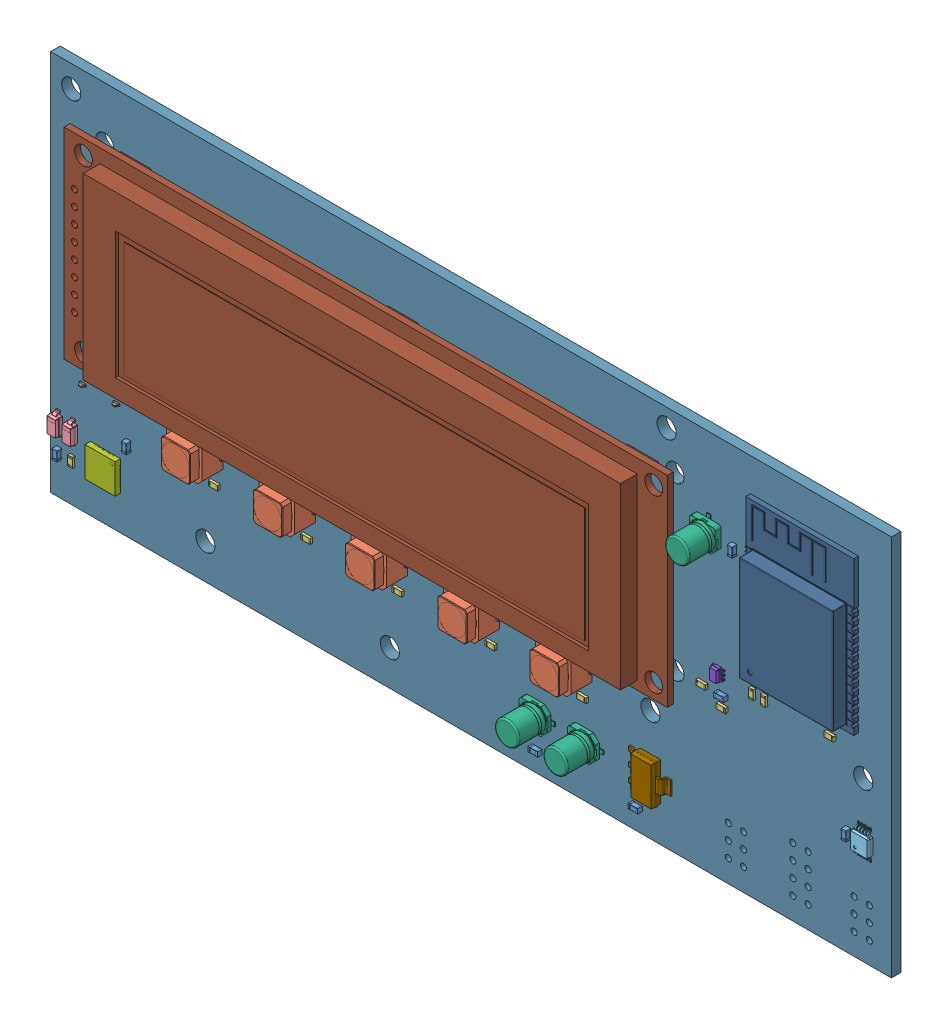
SolidWorks assembly MiliOhmMeter, configuration Default. Lengths in mm.
Overall size (140.08 63.63 18.73).
86 component instances, 14 part files, 0 mates.
Components (placement in the parent):
- MiliOhmMeter.step-1: MiliOhmMeter.step [Default] at origin size (140.08 63.63 18.73)
  - C_0603_1608Metric.step-1: C_0603_1608Metric.step [Default] at (62.9031 -14.3637 1.65) x (0 -1 0) z (0 0 1) size (1.6 0.8 0.8)
    - SOLID.step-1: SOLID.step [Default] at origin size (1.6 0.8 0.8)
  - C_0603_1608Metric.step-2: C_0603_1608Metric.step [Default] at (-15.1635 -16.8021 1.65) size (1.6 0.8 0.8)
    - SOLID.step-1: SOLID.step [Default] at origin size (1.6 0.8 0.8)
  - C_0603_1608Metric.step-3: C_0603_1608Metric.step [Default] at (-68.5419 -25.2603 1.65) x (0 -1 0) z (0 0 1) size (1.6 0.8 0.8)
    - SOLID.step-1: SOLID.step [Default] at origin size (1.6 0.8 0.8)
  - SW_SPST_Alps_SKPMAME010.step-1: SW_SPST_Alps_SKPMAME010.step [Default] at (-28.2355 -11.4021 1.65) x (1 0 0) z (0 -1 0) size (6.7 5 6)
    - COMPOUND.step-1: COMPOUND.step [Default] at origin size (6.7 5 6)
  - R_0603_1608Metric.step-1: R_0603_1608Metric.step [Default] at (47.1043 -2.0701 1.65) x (0 -1 0) z (0 0 1) size (1.6 0.8 0.45)
    - SOLID-0.step-1: SOLID-0.step [Default] at origin size (1.6 0.8 0.45)
  - D_SOD-123.step-1: D_SOD-123.step [Default] at (-68.6435 -20.9931 1.65) x (0 -1 0) z (0 0 1) size (3.8 1.6 1.25)
    - SOLID-1.step-1: SOLID-1.step [Default] at origin size (3.8 1.6 1.25)
  - C_0603_1608Metric.step-4: C_0603_1608Metric.step [Default] at (15.5575 -16.8021 1.65) size (1.6 0.8 0.8)
    - SOLID.step-1: SOLID.step [Default] at origin size (1.6 0.8 0.8)
  - SW_SPST_Alps_SKPMAME010.step-2: SW_SPST_Alps_SKPMAME010.step [Default] at (-12.8755 -11.4021 1.65) x (1 0 0) z (0 -1 0) size (6.7 5 6)
    - COMPOUND.step-1: COMPOUND.step [Default] at origin size (6.7 5 6)
  - R_0603_1608Metric.step-2: R_0603_1608Metric.step [Default] at (-27.1145 -16.8021 1.65) x (-1 0 0) z (0 0 1) size (1.6 0.8 0.45)
    - SOLID-0.step-1: SOLID-0.step [Default] at origin size (1.6 0.8 0.45)
  - C_0603_1608Metric.step-5: C_0603_1608Metric.step [Default] at (0.3175 -16.8021 1.65) size (1.6 0.8 0.8)
    - SOLID.step-1: SOLID.step [Default] at origin size (1.6 0.8 0.8)
  - SW_SPST_Alps_SKPMAME010.step-3: SW_SPST_Alps_SKPMAME010.step [Default] at (17.8445 -11.4021 1.65) x (1 0 0) z (0 -1 0) size (6.7 5 6)
    - COMPOUND.step-1: COMPOUND.step [Default] at origin size (6.7 5 6)
  - TSSOP-10_3x3mm_P0.5mm.step-1: TSSOP-10_3x3mm_P0.5mm.step [Default] at (65.659 -14.2621 1.65) x (0 1 0) z (0 0 1) size (4.9 3 1)
    - SOLID-2.step-1: SOLID-2.step [Default] at origin size (4.9 3 1)
  - C_Elec_4x5.4.step-1: C_Elec_4x5.4.step [Default] at (11.3665 -23.1521 1.65) x (-1 0 0) z (0 0 1) size (5.74 5.46 5.4)
    - COMPOUND-3.step-1: COMPOUND-3.step [Default] at origin size (5.74 5.46 5.4)
  - D_SOD-123.step-2: D_SOD-123.step [Default] at (-66.1289 -20.9931 1.65) x (0 -1 0) z (0 0 1) size (3.8 1.6 1.25)
    - SOLID-1.step-1: SOLID-1.step [Default] at origin size (3.8 1.6 1.25)
  - R_0603_1608Metric.step-3: R_0603_1608Metric.step [Default] at (-11.8745 -16.8021 1.65) x (-1 0 0) z (0 0 1) size (1.6 0.8 0.45)
    - SOLID-0.step-1: SOLID-0.step [Default] at origin size (1.6 0.8 0.45)
  - SW_SPST_Alps_SKPMAME010.step-4: SW_SPST_Alps_SKPMAME010.step [Default] at (2.4845 -11.4021 1.65) x (1 0 0) z (0 -1 0) size (6.7 5 6)
    - COMPOUND.step-1: COMPOUND.step [Default] at origin size (6.7 5 6)
  - R_0603_1608Metric.step-4: R_0603_1608Metric.step [Default] at (42.1005 -6.6421 1.65) x (-1 0 0) z (0 0 1) size (1.6 0.8 0.45)
    - SOLID-0.step-1: SOLID-0.step [Default] at origin size (1.6 0.8 0.45)
  - C_0603_1608Metric.step-6: C_0603_1608Metric.step [Default] at (42.0497 -4.9149 1.65) x (-1 0 0) z (0 0 1) size (1.6 0.8 0.8)
    - SOLID.step-1: SOLID.step [Default] at origin size (1.6 0.8 0.8)
  - C_0603_1608Metric.step-7: C_0603_1608Metric.step [Default] at (-30.4165 -16.8021 1.65) size (1.6 0.8 0.8)
    - SOLID.step-1: SOLID.step [Default] at origin size (1.6 0.8 0.8)
  - R_0603_1608Metric.step-5: R_0603_1608Metric.step [Default] at (49.0855 -2.0701 1.65) x (0 1 0) z (0 0 1) size (1.6 0.8 0.45)
    - SOLID-0.step-1: SOLID-0.step [Default] at origin size (1.6 0.8 0.45)
  - C_Elec_4x5.4.step-2: C_Elec_4x5.4.step [Default] at (39.7129 17.3355 1.65) x (0 1 0) z (0 0 1) size (5.74 5.46 5.4)
    - COMPOUND-3.step-1: COMPOUND-3.step [Default] at origin size (5.74 5.46 5.4)
  - R_0603_1608Metric.step-6: R_0603_1608Metric.step [Default] at (-66.3321 -25.2603 1.65) x (0 -1 0) z (0 0 1) size (1.6 0.8 0.45)
    - SOLID-0.step-1: SOLID-0.step [Default] at origin size (1.6 0.8 0.45)
  - R_0603_1608Metric.step-7: R_0603_1608Metric.step [Default] at (18.8595 -16.8021 1.65) x (-1 0 0) z (0 0 1) size (1.6 0.8 0.45)
    - SOLID-0.step-1: SOLID-0.step [Default] at origin size (1.6 0.8 0.45)
  - QFN-28-1EP_5x5mm_P0.5mm_EP3.35x3.35mm.step-1: QFN-28-1EP_5x5mm_P0.5mm_EP3.35x3.35mm.step [Default] at (-60.833 -23.5331 1.65) x (0 -1 0) z (0 0 1) size (5 5 0.92)
    - SOLID-4.step-1: SOLID-4.step [Default] at origin size (5 5 0.92)
  - R_0603_1608Metric.step-8: R_0603_1608Metric.step [Default] at (-42.5069 -16.8021 1.65) x (-1 0 0) z (0 0 1) size (1.6 0.8 0.45)
    - SOLID-0.step-1: SOLID-0.step [Default] at origin size (1.6 0.8 0.45)
  - C_0603_1608Metric.step-8: C_0603_1608Metric.step [Default] at (-57.0103 -18.4531 1.65) x (0 1 0) z (0 0 1) size (1.6 0.8 0.8)
    - SOLID.step-1: SOLID.step [Default] at origin size (1.6 0.8 0.8)
  - C_0603_1608Metric.step-9: C_0603_1608Metric.step [Default] at (27.7749 -28.1051 1.65) x (-1 0 0) z (0 0 1) size (1.6 0.8 0.8)
    - SOLID.step-1: SOLID.step [Default] at origin size (1.6 0.8 0.8)
  - SW_SPST_Alps_SKPMAME010.step-5: SW_SPST_Alps_SKPMAME010.step [Default] at (-43.5955 -11.4021 1.65) x (1 0 0) z (0 -1 0) size (6.7 5 6)
    - COMPOUND.step-1: COMPOUND.step [Default] at origin size (6.7 5 6)
  - R_0603_1608Metric.step-9: R_0603_1608Metric.step [Default] at (3.6195 -16.8021 1.65) x (-1 0 0) z (0 0 1) size (1.6 0.8 0.45)
    - SOLID-0.step-1: SOLID-0.step [Default] at origin size (1.6 0.8 0.45)
  - SOT-363_SC-70-6.step-1: SOT-363_SC-70-6.step [Default] at (41.402 -1.9431 1.65) size (2 2 1.05)
    - SOLID-5.step-1: SOLID-5.step [Default] at origin size (2 2 1.05)
  - C_0603_1608Metric.step-10: C_0603_1608Metric.step [Default] at (43.9547 17.1069 1.65) x (0 1 0) z (0 0 1) size (1.6 0.8 0.8)
    - SOLID.step-1: SOLID.step [Default] at origin size (1.6 0.8 0.8)
  - R_0603_1608Metric.step-10: R_0603_1608Metric.step [Default] at (60.0837 -1.7399 1.65) x (-1 0 0) z (0 0 1) size (1.6 0.8 0.45)
    - SOLID-0.step-1: SOLID-0.step [Default] at origin size (1.6 0.8 0.45)
  - SOT-223.step-1: SOT-223.step [Default] at (30.0605 -22.5679 1.65) size (7 6.5 1.7)
    - SOLID-6.step-1: SOLID-6.step [Default] at origin size (7 6.5 1.7)
  - R_0603_1608Metric.step-11: R_0603_1608Metric.step [Default] at (38.7223 -4.9403 1.65) size (1.6 0.8 0.45)
    - SOLID-0.step-1: SOLID-0.step [Default] at origin size (1.6 0.8 0.45)
  - ESP32-WROOM-32.step-1: ESP32-WROOM-32.step [Default] at (55.626 10.6299 1.65) size (18 25.5 3.1)
    - SOLID-7.step-1: SOLID-7.step [Default] at origin size (18 25.5 3.1)
  - C_0603_1608Metric.step-11: C_0603_1608Metric.step [Default] at (11.1125 -28.2321 1.65) x (-1 0 0) z (0 0 1) size (1.6 0.8 0.8)
    - SOLID.step-1: SOLID.step [Default] at origin size (1.6 0.8 0.8)
  - OLED_SSD1322_NHD_256X64.step-1: OLED_SSD1322_NHD_256X64.step [Default] at (-104.132 5.9279 4.15) x (-1 0 0) z (0 1 0) size (100.5 6.3 33.5)
    - COMPOUND-8.step-1: COMPOUND-8.step [Default] at origin size (100.5 6.3 33.5)
  - C_0603_1608Metric.step-12: C_0603_1608Metric.step [Default] at (-45.9105 -16.8021 1.65) size (1.6 0.8 0.8)
    - SOLID.step-1: SOLID.step [Default] at origin size (1.6 0.8 0.8)
  - C_Elec_4x5.4.step-3: C_Elec_4x5.4.step [Default] at (19.4433 -23.1775 1.65) x (-1 0 0) z (0 0 1) size (5.74 5.46 5.4)
    - COMPOUND-3.step-1: COMPOUND-3.step [Default] at origin size (5.74 5.46 5.4)
  - USB_Micro-B_Molex-105133-0031.step-1: USB_Micro-B_Molex-105133-0031.step [Default] at (-61.8617 -13.3051 -4.05) size (8.5 4.45 12.9)
    - COMPOUND-9.step-1: COMPOUND-9.step [Default] at origin size (8.5 4.45 12.9)
  - SW_SPST_CK_RS282G05A3.step-1: SW_SPST_CK_RS282G05A3.step [Default] at (40.894 6.6929 -0.05) x (0 1 0) z (0 0 -1) size (8 3.5 2.5)
    - SOLID-10.step-1: SOLID-10.step [Default] at origin size (8 3.5 2.5)
  - SW_SPST_CK_RS282G05A3.step-2: SW_SPST_CK_RS282G05A3.step [Default] at (40.894 15.4559 -0.05) x (0 1 0) z (0 0 -1) size (8 3.5 2.5)
    - SOLID-10.step-1: SOLID-10.step [Default] at origin size (8 3.5 2.5)
  - MiliOhmMeter PCB.step-1: MiliOhmMeter PCB.step [Default] at origin size (140.08 63.63 1.6)
